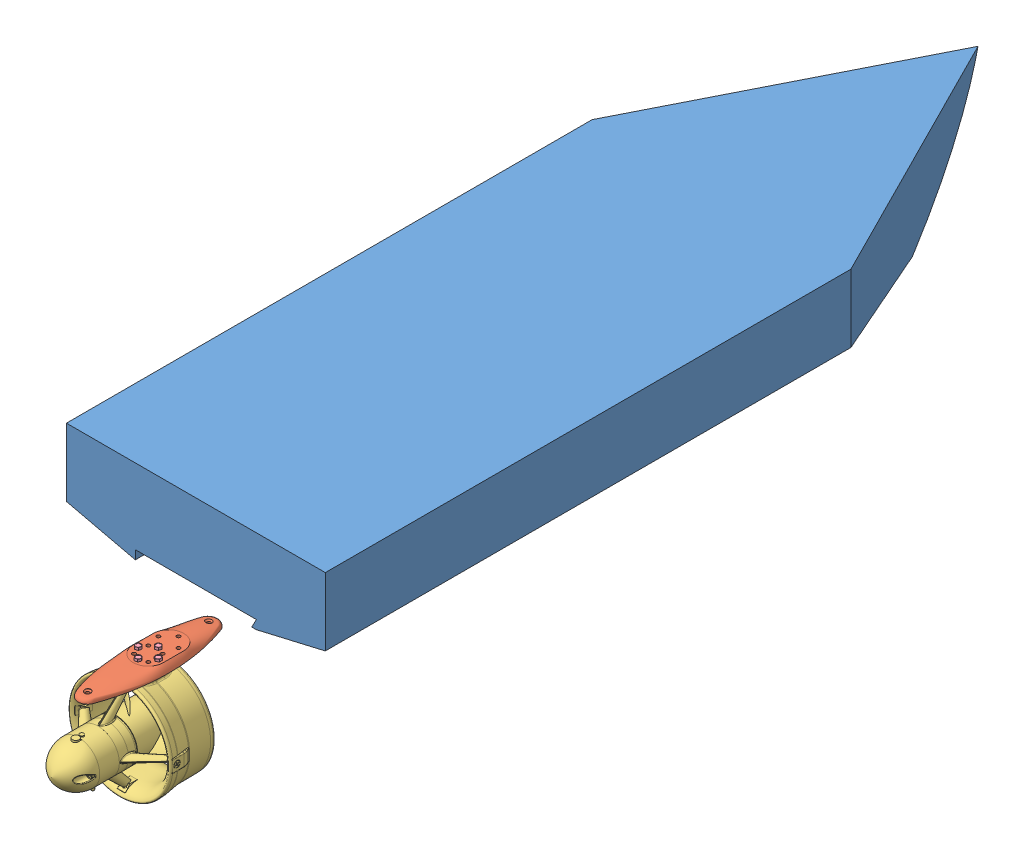
SolidWorks assembly Prototype Assembly, configuration Default. Lengths in mm.
Overall size (244.04 192.8 888.77).
7 component instances, 4 part files, 13 mates.
Components (placement in the parent):
- Actual Boat Prototype-1: Actual Boat Prototype [Scaled] at (274.202 388.5066 644.1198) size (244.04 92.45 737.03)
- T100-P-BRACKET-R1-1: T100-P-BRACKET-R1 [Default] at (289.9785 337.6668 993.786) x (0 0 -1) z (1 0 0) size (132.12 9.13 39.23)
- T200-THRUSTER-BLUEESC-R1-1: T200-THRUSTER-BLUEESC-R1 [Default] at (289.9785 288.6668 999.0378) size (96.71 97.53 131.18)
- hex screw_am-5: hex screw_am [B18.6.7M - M3 x 0.5 x 10 Indented HHMS --10N] at (299.4785 346.3168 993.786) x (0 -1 0) z (0.999596 0 0.028413) size (12.3 5.77 5)
- hex screw_am-6: hex screw_am [B18.6.7M - M3 x 0.5 x 10 Indented HHMS --10N] at (280.4785 346.3168 993.786) x (0 -1 0) z (0.979514 0 0.201378) size (12.3 5.77 5)
- hex screw_am-7: hex screw_am [B18.6.7M - M3 x 0.5 x 10 Indented HHMS --10N] at (289.9785 346.3168 1003.286) x (0 -1 0) z (-0.921143 0 -0.389224) size (12.3 5.77 5)
- hex screw_am-8: hex screw_am [B18.6.7M - M3 x 0.5 x 10 Indented HHMS --10N] at (289.9785 346.3168 984.286) x (0 -1 0) z (0.964435 0 0.26432) size (12.3 5.77 5)
Mates (geometry in assembly coordinates):
- Coincident41: coincident anti-aligned: plane of T100-P-BRACKET-R1-1 through (289.9785 344.0168 993.786) normal (0 1 0); plane of hex screw_am-5 through (299.5212 344.0168 992.2866) normal (0 -1 0)
- Coincident51: coincident anti-aligned: plane of T100-P-BRACKET-R1-1 through (289.9785 344.0168 993.786) normal (0 1 0); plane of hex screw_am-8 through (290.375 344.0168 982.8394) normal (0 -1 0)
- Coincident61: coincident anti-aligned: plane of T100-P-BRACKET-R1-1 through (289.9785 344.0168 993.786) normal (0 1 0); plane of hex screw_am-7 through (289.3947 344.0168 1004.6677) normal (0 -1 0)
- Coincident71: coincident anti-aligned: plane of T100-P-BRACKET-R1-1 through (289.9785 344.0168 993.786) normal (0 1 0); plane of hex screw_am-6 through (280.7806 344.0168 992.3168) normal (0 -1 0)
- Concentric11: concentric aligned: cone of T100-P-BRACKET-R1-1 through (299.4785 337.6668 993.786) axis (0 1 0); cylinder of hex screw_am-5 through (299.4785 371.7168 993.786) axis (0 1 0) radius 1.5
- Concentric21: concentric aligned: cone of T100-P-BRACKET-R1-1 through (289.9785 337.6668 984.286) axis (0 1 0); cylinder of hex screw_am-8 through (289.9785 371.7168 984.286) axis (0 1 0) radius 1.5
- Concentric31: concentric aligned: cone of T100-P-BRACKET-R1-1 through (280.4785 337.6668 993.786) axis (0 1 0); cylinder of hex screw_am-6 through (280.4785 371.7168 993.786) axis (0 1 0) radius 1.5
- Concentric41: concentric aligned: cone of T100-P-BRACKET-R1-1 through (289.9785 337.6668 1003.286) axis (0 1 0); cylinder of hex screw_am-7 through (289.9785 371.7168 1003.286) axis (0 1 0) radius 1.5
- Concentric51: concentric anti-aligned: circle of T200-THRUSTER-BLUEESC-R1-1; cylinder of hex screw_am-5 through (299.4785 371.7168 993.786) axis (0 1 0) radius 1.5
- Concentric61: concentric anti-aligned: circle of T200-THRUSTER-BLUEESC-R1-1; cylinder of hex screw_am-6 through (280.4785 371.7168 993.786) axis (0 1 0) radius 1.5
- Concentric71: concentric anti-aligned: circle of T200-THRUSTER-BLUEESC-R1-1; cylinder of hex screw_am-8 through (289.9785 371.7168 984.286) axis (0 1 0) radius 1.5
- Concentric81: concentric anti-aligned: circle of T200-THRUSTER-BLUEESC-R1-1; cylinder of hex screw_am-7 through (289.9785 371.7168 1003.286) axis (0 1 0) radius 1.5
- Coincident81: coincident anti-aligned: plane of T100-P-BRACKET-R1-1 through (367.8057 337.6668 965.211) normal (0 -1 0); plane of T200-THRUSTER-BLUEESC-R1-1 through (289.9785 337.6668 993.786) normal (0 1 0)
